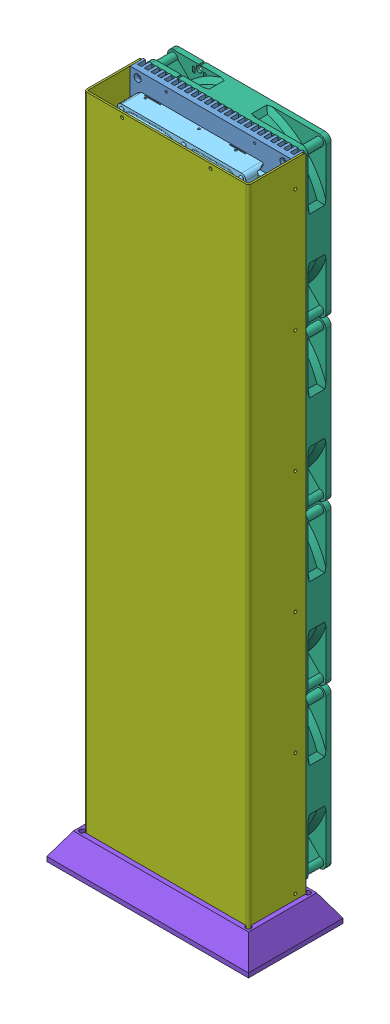
SolidWorks assembly NAS_ASSY, configuration 기본. Lengths in mm.
Overall size (228 755 118).
16 component instances, 8 part files, 3 mates.
Components (placement in the parent):
- NAS_MAIN_ASSY-1: NAS_MAIN_ASSY [기본] at origin size (182 750 93.6)
  - NAS_HEATSINK-1: NAS_HEATSINK [기본] at origin size (182 750 15)
  - MICRONIX_SFX300-1: MICRONIX_SFX300 [기본] at (-20 70 5) size (95.3 120 41.6)
  - NAS_BLOCK-1: NAS_BLOCK [기본] at origin size (35 35 28.5)
  - ASROCK_A520M-ITX-1: ASROCK_A520M-ITX [기본] at (0 220 38) x (1 0 0) z (0 1 0) size (171 38 172.62)
  - HDD-1: HDD [기본] at (-10 365 0) x (0 1 0) z (1 0 0) size (101.5 25.96 145.2)
  - HDD-2: HDD [기본] at (-10 470 0) x (0 1 0) z (1 0 0) size (101.5 25.96 145.2)
  - Silverstone_AP181-1: Silverstone_AP181 [기본] at (0 120 -31) x (0 -1 0) z (-1 0 0) size (179 32 179)
  - Silverstone_AP181-2: Silverstone_AP181 [기본] at (0 300 -31) x (0 -1 0) z (-1 0 0) size (179 32 179)
  - Silverstone_AP181-3: Silverstone_AP181 [기본] at (0 480 -31) x (0 -1 0) z (-1 0 0) size (179 32 179)
  - Silverstone_AP181-4: Silverstone_AP181 [기본] at (0 660 -31) x (0 -1 0) z (-1 0 0) size (179 32 179)
  - HDD-5: HDD [기본] at (-10 575 0) x (0 1 0) z (1 0 0) size (101.5 25.96 145.2)
  - HDD-6: HDD [기본] at (-10 680 0) x (0 1 0) z (1 0 0) size (101.5 25.96 145.2)
- NAS_COVER_ASSY-1: NAS_COVER_ASSY [기본] at origin size (186 750 65)
  - NAS_COVER-1: NAS_COVER [기본] at origin size (186 750 65)
- NAS_FOOT-1: NAS_FOOT [기본] at origin size (228 30 107)
Mates (geometry in assembly coordinates):
- 일치26: coordinate: point of NAS_COVER_ASSY-1
- 일치27: coordinate: unknown of NAS_MAIN_ASSY-1
- 일치33: coordinate: unknown of NAS_FOOT-1
